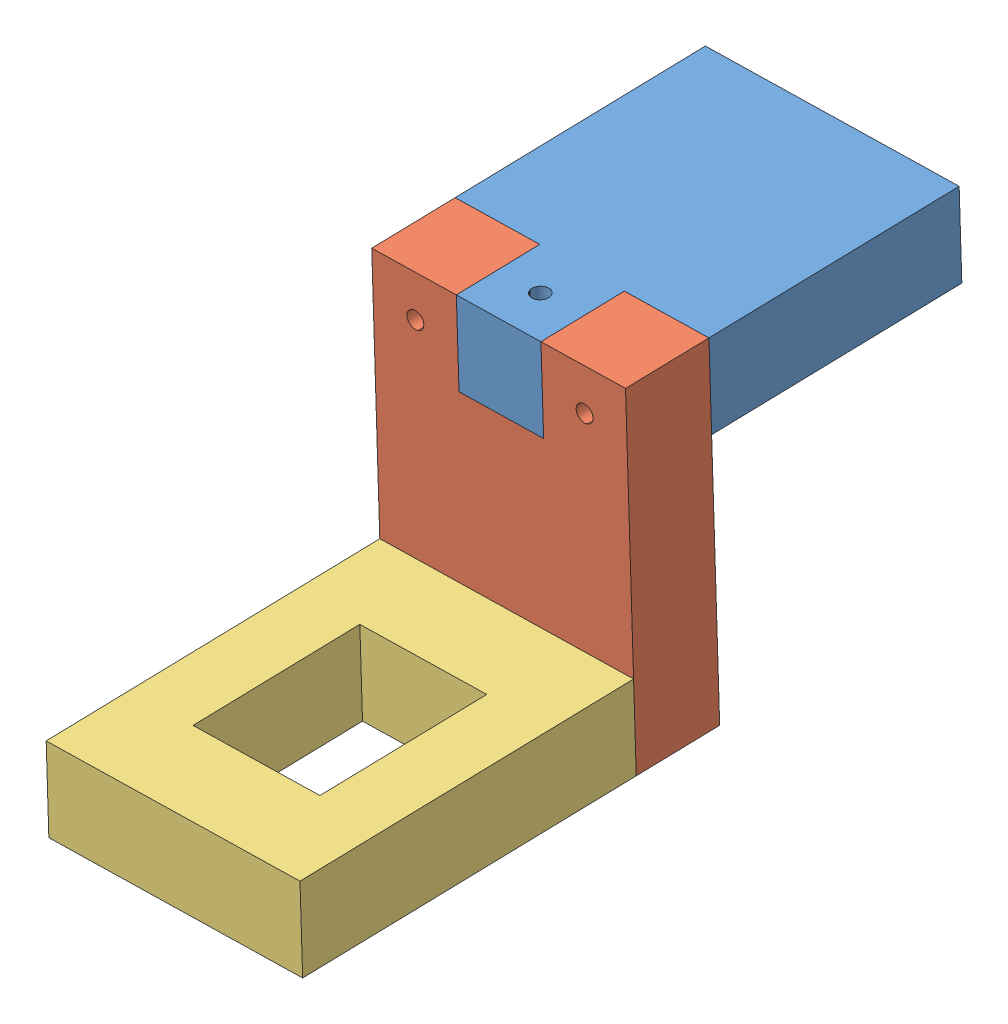
SolidWorks assembly Trailer_Hitch, configuration Default. Lengths in mm.
Overall size (19.78 26.55 50.7).
3 component instances, 3 part files, 6 mates.
Components (placement in the parent):
- Trailer_Arm_H-1: Trailer_Arm_H [Default] at (-102.7636 52.344 61.8357) x (0.99987 0.014537 -0.006979) z (0.014413 -0.999743 -0.017505) size (19.05 25.4 6.35)
- Trailer_Arm_V-1: Trailer_Arm_V [Default] at (-102.2597 26.619 80.4377) x (0.99987 0.014537 -0.006979) z (0.007232 -0.017403 0.999822) size (19.05 25.4 6.35)
- Trailer_Hook-1: Trailer_Hook [Default] at (-102.3512 32.9674 80.5488) x (0.99987 0.014537 -0.006979) z (0.014413 -0.999743 -0.017505) size (19.05 31.75 6.35)
Mates (geometry in assembly coordinates):
- Coincident4: coincident aligned: plane of Trailer_Arm_H-1 through (-102.4883 45.5536 87.12) normal (0.007232 -0.017403 0.999822); plane of Trailer_Arm_V-1 through (-102.2138 26.5085 86.7865) normal (0.007232 -0.017403 0.999822)
- Coincident5: coincident aligned: plane of Trailer_Arm_H-1 through (-83.6245 46.2726 61.5916) normal (0.99987 0.014537 -0.006979); plane of Trailer_Arm_V-1 through (-83.1663 26.7855 86.6536) normal (0.99987 0.014537 -0.006979)
- Coincident6: coincident anti-aligned: plane of Trailer_Arm_H-1 through (-102.672 45.9956 61.7245) normal (0.014413 -0.999743 -0.017505); plane of Trailer_Arm_V-1 through (-96.1851 45.7564 80.7268) normal (-0.014413 0.999743 0.017505)
- Coincident7: coincident aligned: plane of Trailer_Arm_V-1 through (-102.2138 26.5085 86.7865) normal (-0.99987 -0.014537 0.006979); plane of Trailer_Hook-1 through (-102.2597 26.619 80.4377) normal (-0.99987 -0.014537 0.006979)
- Coincident8: coincident aligned: plane of Trailer_Arm_V-1 through (-102.2597 26.619 80.4377) normal (-0.007232 0.017403 -0.999822); plane of Trailer_Hook-1 through (-102.2597 26.619 80.4377) normal (-0.007232 0.017403 -0.999822)
- Coincident12: coincident anti-aligned: plane of Trailer_Arm_V-1 through (-96.0021 33.0597 80.5045) normal (0.014413 -0.999743 -0.017505); plane of Trailer_Hook-1 through (-102.3512 32.9674 80.5488) normal (-0.014413 0.999743 0.017505)
